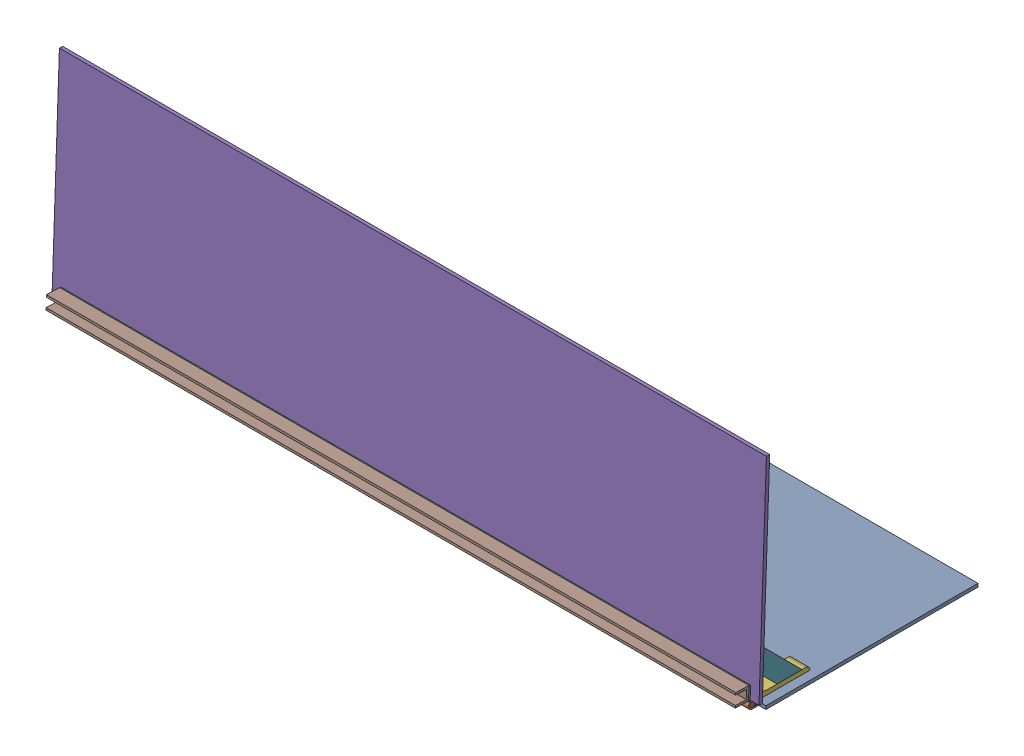
SolidWorks assembly FE-00014_ASM, configuration Default. Lengths in mm.
Overall size (1016 321.79 336.1).
9 component instances, 7 part files, 0 mates.
Components (placement in the parent):
- FE-00014-01-1: FE-00014-01 [Default] at origin size (1016 4.76 304.8)
- FE-00014-02_ASM-1: FE-00014-02_ASM [Default] at (0 -2.286 159.4485) x (1 0 0) z (0 -1 0) size (990.6 31.05 31.22)
  - 01_39_INCH-1: 01_39_INCH [Default] at origin size (990.6 30.86 10.92)
  - 02_39_INCH-1: 02_39_INCH [Default] at (0 5.4577 -5.6516) x (-1 0 0) z (0 0.999391 -0.034899) size (990.6 30.86 10.92)
  - 03_39_INCH-1: 03_39_INCH [Default] at (0 0 -5.461) size (990.6 6.35 6.35)
- FE-00014-01-2: FE-00014-01 [Default] at (0 162.6372 157.0569) x (1 0 0) z (0 0.999391 -0.034899) size (1016 4.76 304.8)
- FE-00014-04-1: FE-00014-04 [Default] at (482.6 4.7625 152.4) x (1 0 0) z (0 -1 0) size (25.4 76.2 76.2)
- FE-00014-05-1: FE-00014-05 [Default] at (495.3 40.2983 116.8642) x (0 0.707107 0.707107) z (0 0.707107 -0.707107) size (82.55 25.4 25.4)
- FE-00014-03-1: FE-00014-03 [Default] at (0 19.929 164.3278) x (1 0 0) z (0 -0.034899 -0.999391) size (990.6 19.05 19.05)
